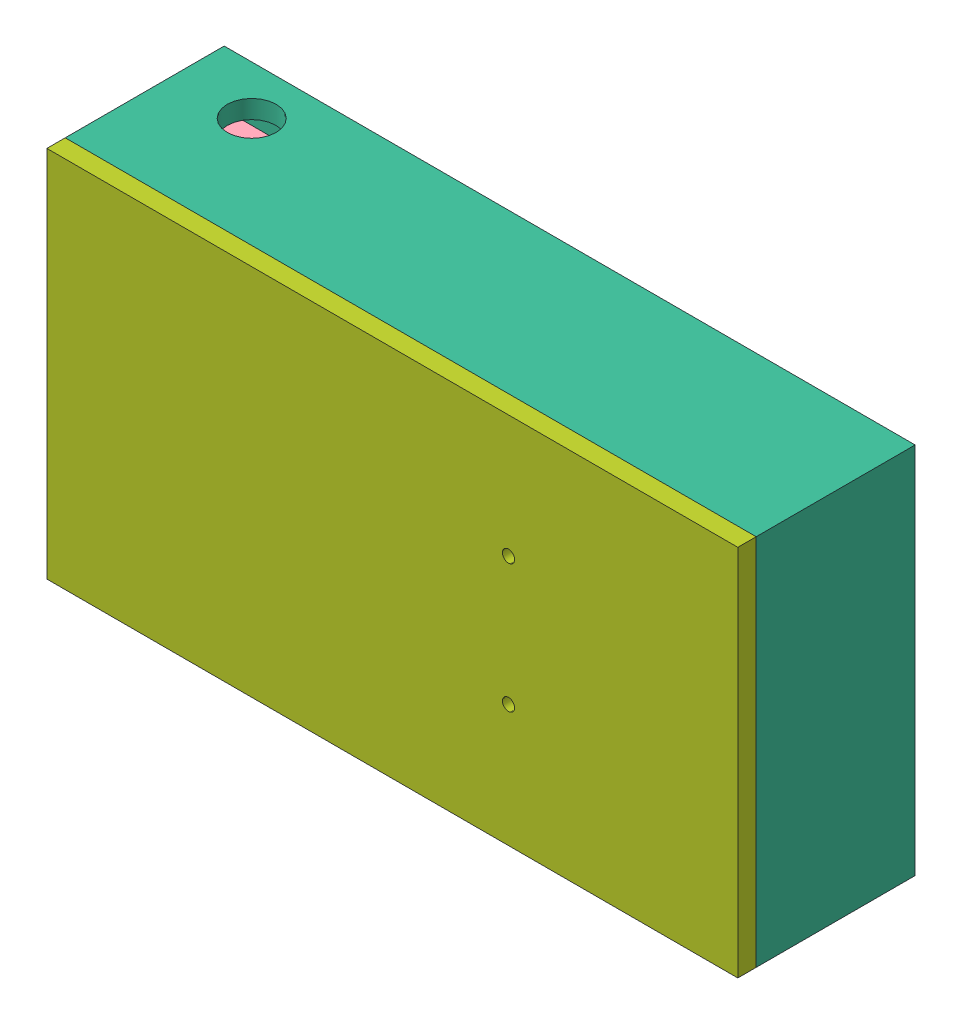
SolidWorks assembly EBoxAssembly, configuration Default. Lengths in mm.
Overall size (113 61 29).
7 component instances, 7 part files, 18 mates.
Components (placement in the parent):
- Arduino-1: Arduino [Default] at (11.969 -9.9585 0.4498) size (34 18.04 4)
- battery-1: battery [Default] at (21.969 -36.9585 -4.5502) x (0 -1 0) z (0 0 1) size (52 27 18)
- BluetoothTransmitter-1: BluetoothTransmitter [Default] at (11.969 -31.9585 0.4498) size (45 17.04 9)
- PCB-1: PCB [Default] at (11.969 -36.9585 -4.5502) size (65 50 3)
- audioJack-1: audioJack [Default] at (-45.031 13.0415 0.4498) x (1 0 0) z (0 -1 0) size (6 4 10)
- OuterBox-1: OuterBox [Default] at (-58.031 19.0415 -7.5502) x (-1 0 0) z (0 0 1) size (113 61 26)
- BoxCover-1: BoxCover [Default] at (-58.031 -41.9585 21.4498) x (-1 0 0) z (0 0 -1) size (113 61 3)
Mates (geometry in assembly coordinates):
- Coincident1: coincident aligned: plane of Arduino-1 through (11.969 -9.9585 0.4498) normal (0 0 -1); plane of BluetoothTransmitter-1 through (11.969 -31.9585 0.4498) normal (0 0 -1)
- Distance2: distance = 10 mm anti-aligned: plane of battery-1 through (21.969 13.0415 13.4498) normal (-1 0 0); plane of BluetoothTransmitter-1 through (11.969 -14.9585 8.4498) normal (1 0 0)
- Width2: width aligned: plane of battery-1 through (48.969 -36.9585 13.4498) normal (0 -1 0); plane of battery-1 through (48.969 13.0415 13.4498) normal (0 1 0); plane of BluetoothTransmitter-1 through (-33.031 -31.9585 8.4498) normal (0 -1 0); plane of Arduino-1 through (-22.031 8.0415 3.4498) normal (0 1 0)
- Coincident2: coincident aligned: plane of Arduino-1 through (11.969 8.0415 3.4498) normal (1 0 0); plane of BluetoothTransmitter-1 through (11.969 -14.9585 8.4498) normal (1 0 0)
- Distance3: distance = 5 mm anti-aligned: plane of Arduino-1 through (-22.031 -9.9585 3.4498) normal (0 -1 0); plane of BluetoothTransmitter-1 through (-33.031 -14.9585 8.4498) normal (0 1 0)
- Distance5: distance = 2 mm anti-aligned: plane of PCB-1 through (11.969 -36.9585 -1.5502) normal (0 0 1); plane of Arduino-1 through (11.969 -9.9585 0.4498) normal (0 0 -1)
- Width3: width aligned: plane of PCB-1 through (-53.031 13.0415 -1.5502) normal (0 1 0); plane of PCB-1 through (-53.031 -36.9585 -1.5502) normal (0 -1 0); plane of Arduino-1 through (-22.031 8.0415 3.4498) normal (0 1 0); plane of BluetoothTransmitter-1 through (-33.031 -31.9585 8.4498) normal (0 -1 0)
- Coincident6: coincident aligned: plane of BluetoothTransmitter-1 through (11.969 -14.9585 8.4498) normal (1 0 0); plane of PCB-1 through (11.969 13.0415 -1.5502) normal (1 0 0)
- Coincident8: coincident anti-aligned: plane of PCB-1 through (11.969 -36.9585 -1.5502) normal (0 0 1); plane of audioJack-1 through (-47.031 3.0415 -1.5502) normal (0 0 -1)
- Coincident9: coincident aligned: plane of PCB-1 through (-53.031 13.0415 -1.5502) normal (0 1 0); plane of audioJack-1 through (-45.031 13.0415 0.4498) normal (0 1 0)
- Distance6: distance = 6 mm aligned: plane of audioJack-1 through (-47.031 3.0415 2.4498) normal (-1 0 0); plane of PCB-1 through (-53.031 13.0415 -1.5502) normal (-1 0 0)
- Coincident11: coincident aligned: plane of battery-1 through (21.969 -36.9585 -4.5502) normal (0 0 -1); plane of PCB-1 through (11.969 -36.9585 -4.5502) normal (0 0 -1)
- Distance7: distance = 3 mm anti-aligned: plane of battery-1 through (48.969 13.0415 13.4498) normal (1 0 0); plane of OuterBox-1 through (51.969 -38.9585 18.4498) normal (-1 0 0)
- Distance8: distance = 2000 mm anti-aligned: plane of battery-1 through (21.969 -36.9585 -4.5502) normal (0 0 -1); plane of OuterBox-1 through (-58.031 19.0415 -4.5502) normal (0 0 1)
- Distance9: distance = 2 mm anti-aligned: plane of battery-1 through (48.969 -36.9585 13.4498) normal (0 -1 0); plane of OuterBox-1 through (14.969 -38.9585 18.4498) normal (0 1 0)
- Distance10: distance = 0 mm aligned: plane of OuterBox-1 through (-58.031 -41.9585 18.4498) normal (-1 0 0); plane of BoxCover-1 through (-58.031 19.0415 18.4498) normal (-1 0 0)
- Distance12: distance = 0 mm aligned: plane of BoxCover-1 through (54.969 -41.9585 18.4498) normal (0 -1 0); plane of OuterBox-1 through (54.969 -41.9585 18.4498) normal (0 -1 0)
- Coincident17: coincident anti-aligned: plane of OuterBox-1 through (-58.031 19.0415 18.4498) normal (0 0 1); plane of BoxCover-1 through (-58.031 -41.9585 18.4498) normal (0 0 -1)
